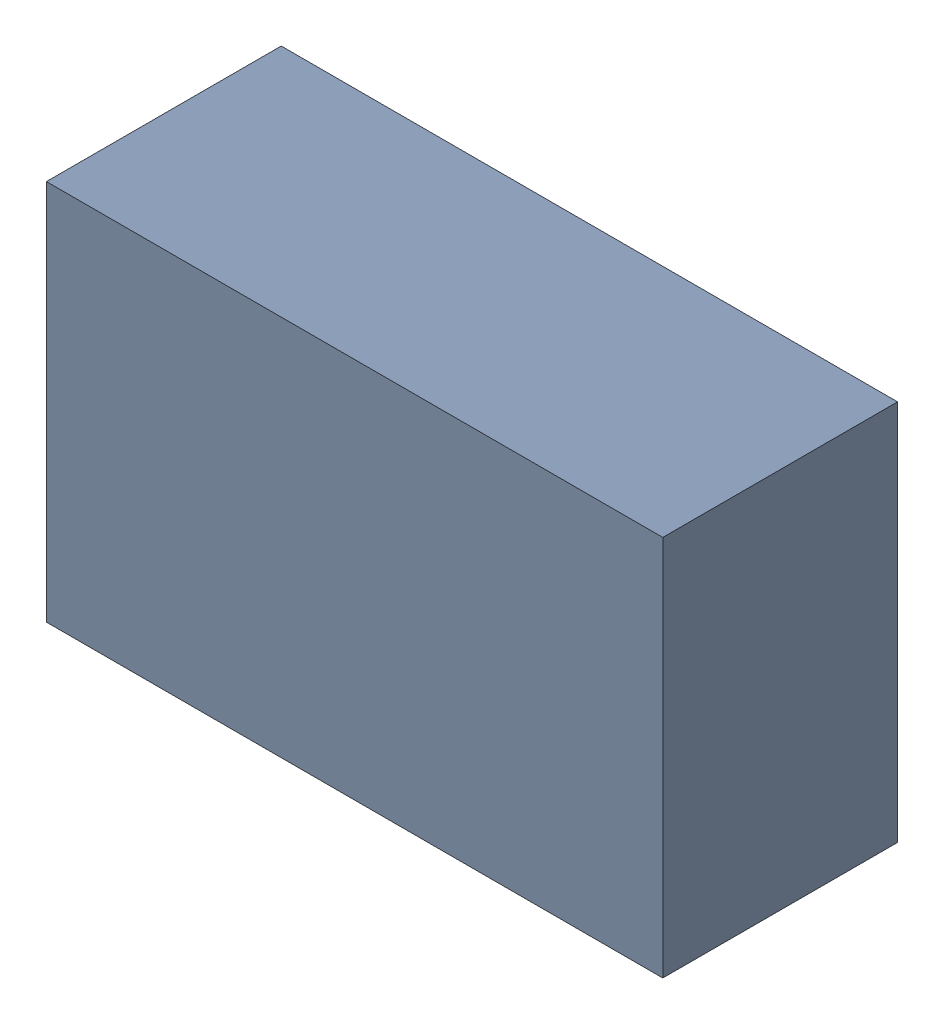
SolidWorks assembly 6297726448.step, configuration Default. Lengths in mm.
Overall size (1.05 0.65 0.4).
4 component instances, 3 part files, 0 mates.
Components (placement in the parent):
- Body (10).step-1: Body (10).step [Default] at (-0.525 -0.325 0) size (1.05 0.65 0.4)
- bigPin.step-1: bigPin.step [Default] at (0.175 -0.275 -0.0033) size (0.3 0.55 0.01)
- smallPine.step-1: smallPine.step [Default] at (-0.475 -0.275 -0.0033) size (0.3 0.2 0.01)
- smallPine.step-2: smallPine.step [Default] at (-0.475 0.075 -0.0033) size (0.3 0.2 0.01)
